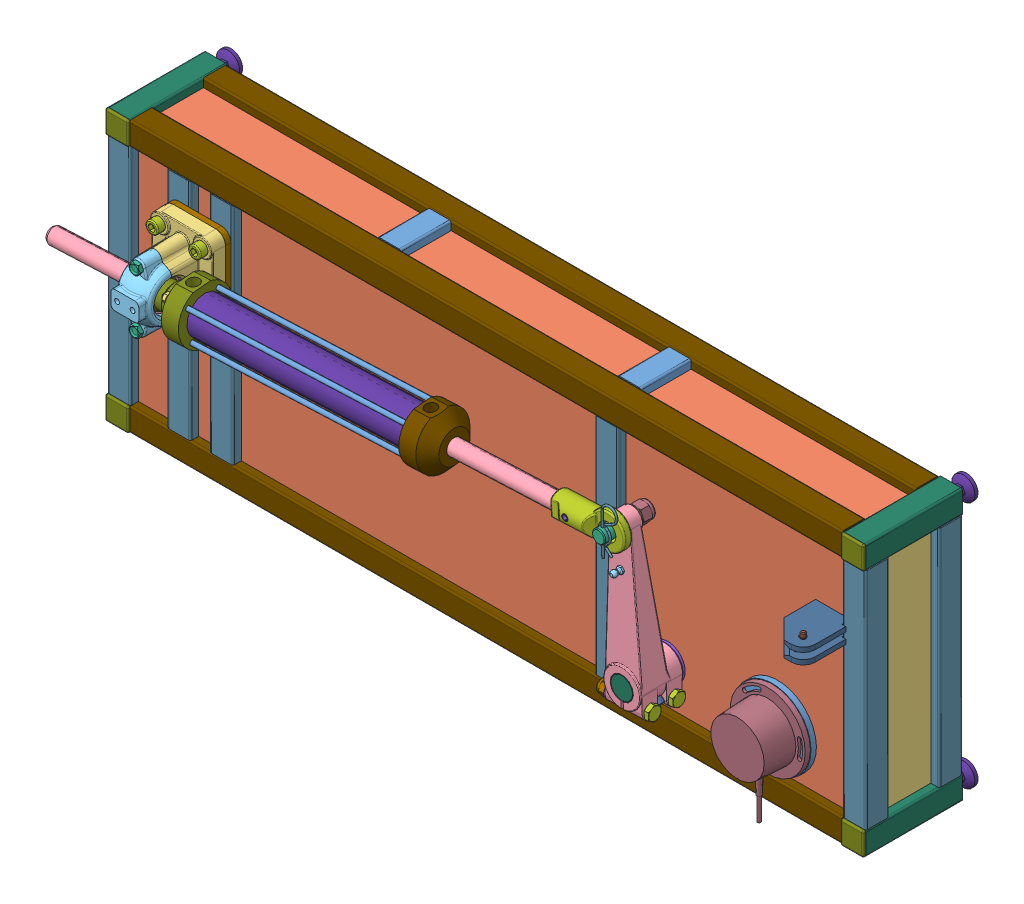
SolidWorks assembly _EF_BancPH_ivan, configuration Défaut. Lengths in mm.
Overall size (1049.48 365 265.04).
99 component instances, 44 part files, 5 mates.
Components (placement in the parent):
- SE_Bati-1: SE_Bati [Défaut] at (-854.2974 517.993 336.3886) size (1036.78 365 242.75)
  - AP_Platine-2: AP_Platine [Défaut] at (240.684 155 59.4838) x (1 0 0) z (0 -1 0) size (1015.78 221.9 344)
    - Bati_CaleRF300-1: Bati_CaleRF300 [Défaut] at (43.2758 -59.4838 151.6207) x (-0.999717 0 0.023798) z (0 1 0) size (100 100 7)
    - Bati_Platine-1: Bati_Platine [Défaut] at (-240.684 -59.4838 155) x (1 0 0) z (0 1 0) size (1015.78 308 8)
    - AP_Palier monte-1: AP_Palier monte [Défaut] at (-834.184 -41.4838 0) x (0 0 -1) z (0 1 0) size (110.24 80.24 142)
      - Palier support VHM32 DTP-1: Palier support VHM32 DTP [Défaut] at origin size (110.24 80.24 51)
      - demicoussinet-1: demicoussinet [Défaut] at (0 0 51) x (0 1 0) z (1 0 0) size (25.2 24 52)
      - demicoussinet-2: demicoussinet [Défaut] at (0 0 51) x (0 1 0) z (-1 0 0) size (25.2 24 52)
      - Couvercle palier V2 H32-1: Couvercle palier V2 H32 [Défaut] at (0 0 51) size (88 42 39)
      - vis H-M8-40-1: vis H-M8-40 [M12-1.75 x 45] at (35 0 73) x (0.992169 -0.124905 0) z (0 0 1) size (13.93 15.94 45.5)
      - vis H-M8-40-2: vis H-M8-40 [M12-1.75 x 45] at (-35 0 73) x (-0.586563 0.809903 0) z (0 0 1) size (13.93 15.94 45.5)
      - Vis CHC M10x70-1: Vis CHC M10x70 [ISO 4762 M10 x 60 --- 60N] at (-42.5 27.5 28) x (0 0 -1) z (1 0 0) size (80 16 16)
      - Vis CHC M10x70-2: Vis CHC M10x70 [ISO 4762 M10 x 60 --- 60N] at (42.5 27.5 28) x (0 0 -1) z (1 0 0) size (80 16 16)
      - Vis CHC M10x70-3: Vis CHC M10x70 [ISO 4762 M10 x 60 --- 60N] at (-42.5 -27.5 28) x (0 0 -1) z (1 0 0) size (80 16 16)
      - Vis CHC M10x70-4: Vis CHC M10x70 [ISO 4762 M10 x 60 --- 60N] at (42.5 -27.5 28) x (0 0 -1) z (1 0 0) size (80 16 16)
    - Bati_Coussinet-1: Bati_Coussinet [Défaut] at (-240.684 -55.4838 155) x (0.374812 0 0.927101) z (-0.927101 0 0.374812) size (45 50 45)
    - Bati_CaleSupport-1: Bati_CaleSupport [Défaut] at (-240.684 -48.4838 155) x (1 0 0) z (0 1 0) size (80 110 7)
    - AP_Poulie_Support-1: AP_Poulie_Support [Défaut] at (0 -4 0) size (50 179.85 32)
      - Poulie_Support-1: Poulie_Support [Défaut] at (-14.684 -4.5338 0) size (50 179.85 20)
      - Poulie_Axe-1: Poulie_Axe [Défaut] at (-14.684 -4.5338 10) x (0 0 -1) z (0 1 0) size (32 12 12)
      - ring_3am1-6-1: ring_3am1-6 [Default] at (-14.684 -4.5338 -11.6) x (-0.707285 -0.706928 0) z (0 0 1) size (6.95 7.81 0.4)
    - Capteur_Corps-1: Capteur_Corps [Default] at (-98.684 -7.4838 155) x (0 -1 0) z (-1 0 0) size (45 145.25 98.5)
    - Rexroth30x30x290-1: Rexroth30x30x290 [Défaut] at (-861.684 -63.4838 -84) size (30 30 290)
    - Rexroth30x30x290-2: Rexroth30x30x290 [Défaut] at (-806.684 -63.4838 -84) size (30 30 290)
  - AP_Cadre-2: AP_Cadre [Défaut] at (-699 -66 -114.75) size (980 350 148)
    - AP_Poteau-1: AP_Poteau [Défaut] at origin size (30 30 148)
      - Rexroth30x30x125-1: Rexroth30x30x125 [Défaut] at origin size (30 30 125)
      - Rexroth-30x30_Chapeau-1: Rexroth-30x30_Chapeau [Défaut] at (0 0 125) size (30 30 3)
      - Rexroth-PiedRotul8x30-1: Rexroth-PiedRotul8x30 [Défaut] at (0 0 -20) x (1 0 0) z (0 -1 0) size (30 65 30)
    - AP_Poteau-2: AP_Poteau [Défaut] at (0 320 0) size (30 30 148)
      - Rexroth30x30x125-1: Rexroth30x30x125 [Défaut] at origin size (30 30 125)
      - Rexroth-30x30_Chapeau-1: Rexroth-30x30_Chapeau [Défaut] at (0 0 125) size (30 30 3)
      - Rexroth-PiedRotul8x30-1: Rexroth-PiedRotul8x30 [Défaut] at (0 0 -20) x (1 0 0) z (0 -1 0) size (30 65 30)
    - AP_Poteau-3: AP_Poteau [Défaut] at (950 0 0) size (30 30 148)
      - Rexroth30x30x125-1: Rexroth30x30x125 [Défaut] at origin size (30 30 125)
      - Rexroth-30x30_Chapeau-1: Rexroth-30x30_Chapeau [Défaut] at (0 0 125) size (30 30 3)
      - Rexroth-PiedRotul8x30-1: Rexroth-PiedRotul8x30 [Défaut] at (0 0 -20) x (1 0 0) z (0 -1 0) size (30 65 30)
    - AP_Poteau-4: AP_Poteau [Défaut] at (950 320 0) size (30 30 148)
      - Rexroth30x30x125-1: Rexroth30x30x125 [Défaut] at origin size (30 30 125)
      - Rexroth-30x30_Chapeau-1: Rexroth-30x30_Chapeau [Défaut] at (0 0 125) size (30 30 3)
      - Rexroth-PiedRotul8x30-1: Rexroth-PiedRotul8x30 [Défaut] at (0 0 -20) x (1 0 0) z (0 -1 0) size (30 65 30)
    - Rexroth30x30x920-1: Rexroth30x30x920 [Défaut] at (935 0 110.75) x (0 0 1) z (-1 0 0) size (30 30 920)
    - Rexroth30x30x920-2: Rexroth30x30x920 [Défaut] at (935 0 15.75) x (0 0 1) z (-1 0 0) size (30 30 920)
    - Rexroth30x30x920-3: Rexroth30x30x920 [Défaut] at (935 320 110.75) x (0 0 1) z (-1 0 0) size (30 30 920)
    - Rexroth30x30x920-4: Rexroth30x30x920 [Défaut] at (935 320 15.75) x (0 0 1) z (-1 0 0) size (30 30 920)
    - Rexroth30x30x290-1: Rexroth30x30x290 [Défaut] at (0 305 110) x (1 0 0) z (0 -1 0) size (30 30 290)
    - Rexroth30x30x290-2: Rexroth30x30x290 [Défaut] at (0 305 15) x (1 0 0) z (0 -1 0) size (30 30 290)
    - Rexroth30x30x290-3: Rexroth30x30x290 [Défaut] at (950 305 110) x (1 0 0) z (0 -1 0) size (30 30 290)
    - Rexroth30x30x290-4: Rexroth30x30x290 [Défaut] at (950 305 15) x (1 0 0) z (0 -1 0) size (30 30 290)
    - Rexroth30x30x065-1: Rexroth30x30x065 [Défaut] at (320 0 30.75) size (30 30 65)
    - Rexroth30x30x065-2: Rexroth30x30x065 [Défaut] at (320 320 30.75) size (30 30 65)
    - Rexroth30x30x065-3: Rexroth30x30x065 [Défaut] at (630 0 30.75) size (30 30 65)
    - Rexroth30x30x065-4: Rexroth30x30x065 [Défaut] at (630 320 30.75) size (30 30 65)
    - Rexroth30x30x290-5: Rexroth30x30x290 [Défaut] at (630 305 15) x (1 0 0) z (0 -1 0) size (30 30 290)
    - Rexroth30x30x290-6: Rexroth30x30x290 [Défaut] at (630 305 110) x (1 0 0) z (0 -1 0) size (30 30 290)
    - Bati_PlaqueFront-1: Bati_PlaqueFront [Défaut] at (6 -4 21.75) x (1 0 0) z (0 -1 0) size (938 83 8)
    - Bati_PlaqueFront-2: Bati_PlaqueFront [Défaut] at (6 316 21.75) x (1 0 0) z (0 -1 0) size (938 83 8)
    - Bati_PlaqueLat-1: Bati_PlaqueLat [Défaut] at (-4 6 104) x (0 1 0) z (-1 0 0) size (308 83 8)
    - Bati_PlaqueLat-2: Bati_PlaqueLat [Défaut] at (946 6 104) x (0 1 0) z (-1 0 0) size (308 83 8)
- SE_Safran-1: SE_Safran [Default] at (-854.2974 517.993 393.8886) x (-0.023422 0.999726 0) z (0 0 1) size (246.66 68.3 196)
  - AP_BrasMeche-1: AP_BrasMeche [Default] at origin size (246.66 68.3 81.56)
    - BrasMeche-1: BrasMeche [Default] at origin size (224 49.77 55.61)
    - RotuleClipBoule-1: RotuleClipBoule [Default] at (130 0 0) x (-0.907146 0.420816 0) z (0 0 -1) size (9.24 8 24.5)
    - Axe-1: Axe [Default] at (180 0 -3) x (0 1 0) z (0 0 1) size (19.33 21.93 61)
    - Vis H M10x60-1: Vis H M10x60 [ISO 4017 - M10 x 60-N] at (-20 -30.4 -10) x (0 1 0) z (0 0 1) size (66.4 18.48 16)
    - Vis H M10x60-2: Vis H M10x60 [ISO 4017 - M10 x 60-N] at (-20 -30.4 -41.5) x (0 1 0) z (0 0 1) size (66.4 18.48 16)
    - Rondelle plate d10x2-1: Rondelle plate d10x2 [Washer ISO 7091 - 10] at (-20 24 -10) x (0 -1 0) z (0 0 1) size (2 20 20)
    - Rondelle plate d10x2-2: Rondelle plate d10x2 [Washer ISO 7091 - 10] at (-20 24 -41.5) x (0 -1 0) z (0 0 1) size (2 20 20)
    - Ecrou Nylstop d10-1: Ecrou Nylstop d10 [ISO 7040-M10-N] at (-20 34.04 -41.5) x (1 0 0) z (0 1 0) size (16 18.48 11.9)
    - Ecrou Nylstop d10-2: Ecrou Nylstop d10 [ISO 7040-M10-N] at (-20 34.04 -10) x (1 0 0) z (0 1 0) size (16 18.48 11.9)
    - Vis Pression M10-1: Vis Pression M10 [ISO 4029 - M10 x 16-N] at (-21.7416 -21.7416 -25.75) x (0.707107 0.707107 0) z (-0.632586 0.632586 -0.446844) size (16 10 10)
    - Vis Pression M10-2: Vis Pression M10 [ISO 4029 - M10 x 16-N] at (-21.8505 21.8505 -25.75) x (0.707107 -0.707107 0) z (0.697844 0.697844 -0.161327) size (16 10 10)
    - Ecrou Hm M5-1: Ecrou Hm M5 [Hexagon Nut ISO - 4036 - M5 - N] at (130 0 -7.5) size (8 9.24 2.7)
    - Rondelle Grower d14-1: Rondelle Grower d14 [Default] at (180 0 -19) x (0.997529 0.070258 0) z (0 0 1) size (23 23.03 3.07)
    - Ecrou Nylstop M14-1: Ecrou Nylstop M14 [ISO 7040-M14-N] at (180 0 -31.1) x (-0.99253 0.121999 0) z (0 0 -1) size (21 24.25 17)
    - Epingle-1: Epingle [Default] at (180 0 22.45) size (62.66 21.16 2.5)
  - ArbreMeche-1: ArbreMeche [Default] at (0 0 -168) size (30 30 170)
- SE_Cylindre-1: SE_Cylindre [Défaut] at (-1286.7008 567.2458 418.7321) x (0.999105 0.042303 0) z (0.020076 -0.474147 0.880217) size (401.2 89.92 90.98)
  - Fond V2H40-1: Fond V2H40 [Défaut] at (-120.379 92.6632 -65.119) x (1 0 0) z (0 0.390169 0.920743) size (89.2 66 70)
  - Tube V2H40-1: Tube V2H40 [Défaut] at (0.721 92.6632 -65.119) size (285 48 48)
  - Nez V2H40-1: Nez V2H40 [Défaut] at (209.721 92.6632 -65.119) x (1 0 0) z (0 0.390169 0.920743) size (47 68 70)
  - Tirant-1: Tirant [Défaut] at (211.721 66.7084 -75.6238) x (0 -0.970448 -0.24131) z (-1 0 0) size (6 6 335)
  - Tirant-2: Tirant [Défaut] at (211.721 118.6179 -54.6142) x (0 -0.624995 0.780629) z (-1 0 0) size (6 6 335)
  - Tirant-3: Tirant [Défaut] at (211.721 103.168 -91.0738) x (0 -0.973252 0.22974) z (-1 0 0) size (6 6 335)
  - Tirant-4: Tirant [Défaut] at (211.721 82.1584 -39.1643) x (0 0.444448 0.895805) z (-1 0 0) size (6 6 335)
  - Rondelle M6-1: Rondelle M6 [Défaut] at (-113.279 118.6179 -54.6142) x (0 -0.383049 0.923728) z (-1 0 0) size (14 14 1.2)
  - Rondelle M6-2: Rondelle M6 [Défaut] at (-113.279 82.1584 -39.1643) x (0 -0.383049 0.923728) z (-1 0 0) size (14 14 1.2)
  - Rondelle M6-3: Rondelle M6 [Défaut] at (-113.279 66.7084 -75.6238) x (0 -0.383049 0.923728) z (-1 0 0) size (14 14 1.2)
  - Rondelle M6-4: Rondelle M6 [Défaut] at (-113.279 103.168 -91.0738) x (0 -0.383049 0.923728) z (-1 0 0) size (14 14 1.2)
  - ecrouM6-1: ecrouM6 [M8-1.25] at (-119.679 103.168 -91.0738) x (0 0 -1) z (1 0 0) size (10.52 12.06 5.91)
  - ecrouM6-2: ecrouM6 [M8-1.25] at (-119.679 66.7084 -75.6238) x (0 0 -1) z (1 0 0) size (10.52 12.06 5.91)
  - ecrouM6-3: ecrouM6 [M8-1.25] at (-119.679 82.1584 -39.1643) x (0 0 -1) z (1 0 0) size (10.52 12.06 5.91)
  - ecrouM6-4: ecrouM6 [M8-1.25] at (-119.679 118.6179 -54.6142) x (0 0 -1) z (1 0 0) size (10.52 12.06 5.91)
- SE_Tige piston-1: SE_Tige piston [Défaut] at (-1438.4937 673.3869 405.3886) x (0.999105 0.042303 0) z (0 0 -1) size (745 45 39.5)
  - tige speciale-1: tige speciale [Défaut] at origin size (688 20 20)
  - Piston VHM40DTP-1: Piston VHM40DTP [Défaut] at (208 0 0) size (25 39.5 39.5)
  - axe de piston-1: axe de piston [Défaut] at (193 0 -17.5) size (8 8 35)
  - EmboutRotule-1: EmboutRotule [Default] at (580.5 0 0) x (0 1 0) z (-1 0 0) size (45 30 89.5)
  - GoupilleFendue-1: GoupilleFendue [Default] at (535.5 0 0) size (8 7.97 30)
Mates (geometry in assembly coordinates):
- Coaxiale2: concentric anti-aligned: cylinder of SE_Bati-1/AP_Platine-2/Bati_Coussinet-1 through (-854.2974 517.993 363.0051) axis (0 0 1) radius 15; cylinder of SE_Safran-1/ArbreMeche-1 through (-854.2974 517.993 395.8886) axis (0 0 -1) radius 15
- Coïncidente2: coincident anti-aligned: plane of SE_Bati-1/AP_Platine-2/Bati_Coussinet-1 through (-848.3004 503.1594 340.3886) normal (0 0 1); circle of SE_Safran-1/AP_BrasMeche-1/BrasMeche-1
- Coaxiale4: concentric: sphere of SE_Bati-1/AP_Platine-2/AP_Palier monte-1/demicoussinet-2; sphere of SE_Cylindre-1/Fond V2H40-1
- Coaxiale5: concentric aligned: cylinder of SE_Cylindre-1/Nez V2H40-1 through (-1102.9064 687.5958 405.3886) axis (-0.999105 -0.042303 0) radius 35; cylinder of SE_Tige piston-1/tige speciale-1 through (-1536.406 669.2412 405.3886) axis (-0.999105 -0.042303 0) radius 10
- Coaxiale9: concentric aligned: circle of SE_Safran-1/AP_BrasMeche-1/Axe-1; circle of SE_Tige piston-1/EmboutRotule-1
